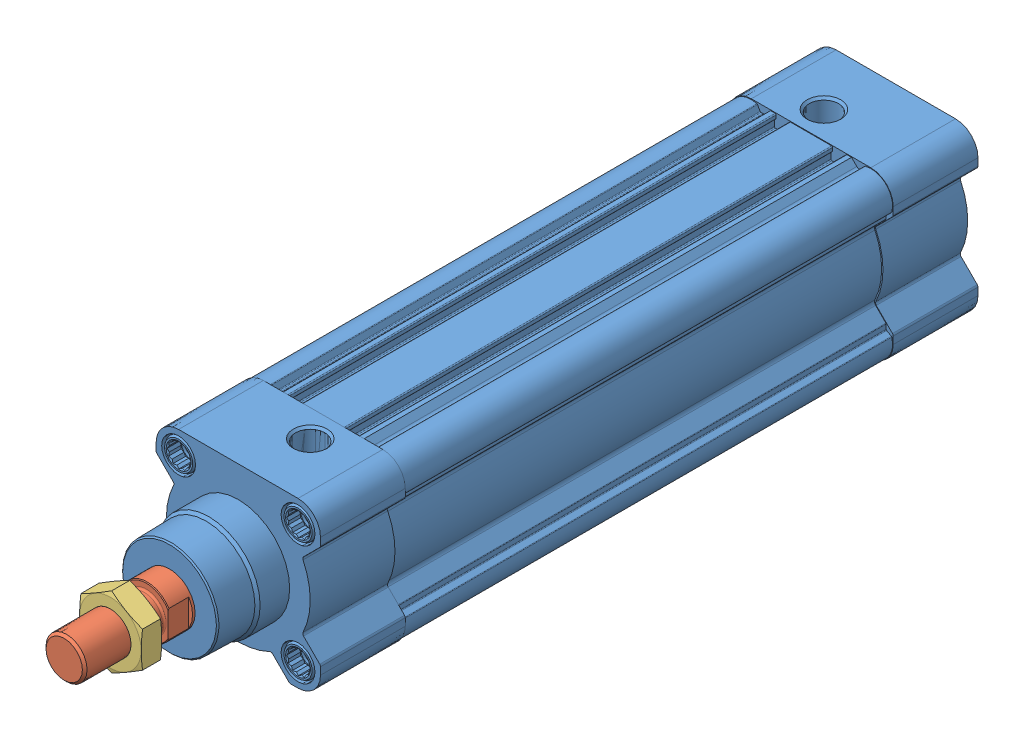
SolidWorks assembly 2102632_DSBC_50_150_PPSA_N3____0_, configuration Default. Lengths in mm.
Overall size (64 64 327.8).
3 component instances, 3 part files, 6 mates.
Components (placement in the parent):
- 1463770_DSBC_50_150_PPSA__Z_0_-1: 1463770_DSBC_50_150_PPSA__Z_0_ [Default] at origin size (64 64 286.8)
- 1463770_DSBC_50_150__K_-1: 1463770_DSBC_50_150__K_ [Default] at origin size (50 50 290.8)
- DIN_439_B___M16x1_5_F_-1: DIN_439_B___M16x1_5_F_ [Default] at (0 0 49.8) x (1 0 0) z (0 -1 0) size (24 8 27.71)
Mates (geometry in assembly coordinates):
- LimitDistance1: limit distance = 0 mm anti-aligned: plane of 1463770_DSBC_50_150_PPSA__Z_0_-1 through (0 0 -223) normal (0 0 1); plane of 1463770_DSBC_50_150__K_-1 through (0 0 -223) normal (0 0 -1)
- Coincident1: coincident anti-aligned: line of 1463770_DSBC_50_150_PPSA__Z_0_-1 through (0 0 80.9) axis (0 0 -1); line of 1463770_DSBC_50_150__K_-1 through (0 0 -50) axis (0 0 1)
- Angle2: planar angle = 1.570796 rad anti-aligned: plane of 1463770_DSBC_50_150__K_-1 through (0 0 0) normal (0 1 0); plane of 1463770_DSBC_50_150_PPSA__Z_0_-1 through (0 0 0) normal (1 0 0)
- Distance1: distance = 0 mm anti-aligned: plane of 1463770_DSBC_50_150__K_-1 through (0 0 49.8) normal (0 0 -1); plane of DIN_439_B___M16x1_5_F_-1 through (0 0 49.8) normal (0 0 1)
- Coincident2: coincident anti-aligned: line of 1463770_DSBC_50_150__K_-1 through (0 0 -80.9) axis (0 0 1); line of DIN_439_B___M16x1_5_F_-1 through (0 0 99.8) axis (0 0 -1)
- Angle5: planar angle = 0 rad aligned: plane of DIN_439_B___M16x1_5_F_-1 through (0 0 49.8) normal (1 0 0); plane of 1463770_DSBC_50_150__K_-1 through (0 0 0) normal (1 0 0)
